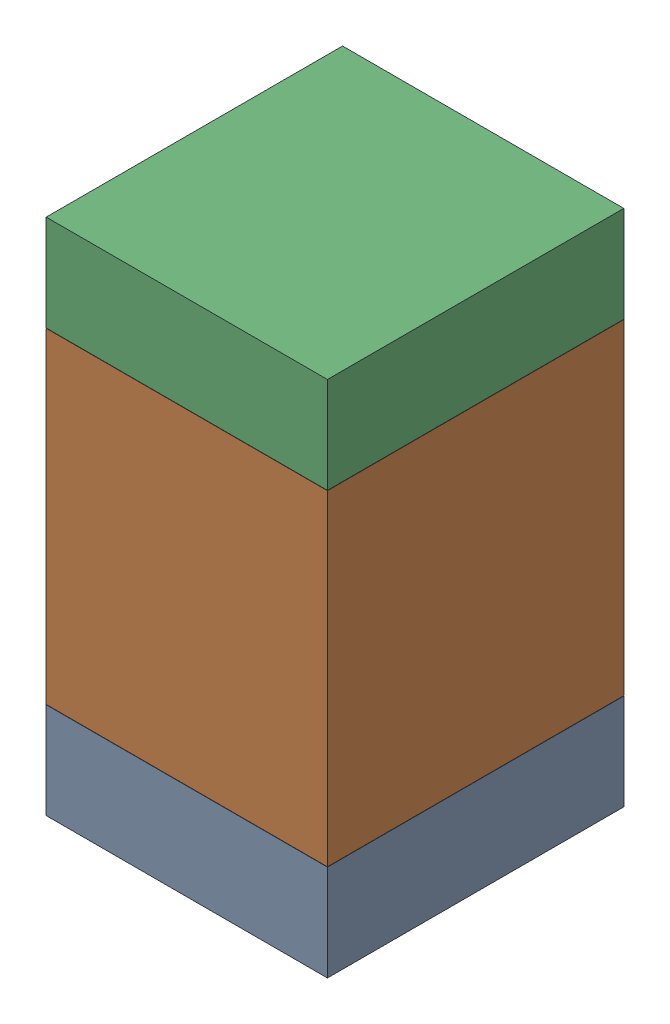
SolidWorks assembly R19, configuration Default. Lengths in mm.
Overall size (0.95 1.75 1).
6 component instances, 2 part files, 0 mates.
Components (placement in the parent):
- 6575495072-1: 6575495072 [Default] at (16.764 11.4795 0) size (0.95 0.32 1)
  - Extruded_6-1: Extruded_6 [Default] at origin size (0.95 0.32 1)
- 6575494912-1: 6575494912 [Default] at (16.764 12.192 0) size (0.95 1.1 1)
  - Extruded_7-1: Extruded_7 [Default] at origin size (0.95 1.1 1)
- 6575495072-2: 6575495072 [Default] at (16.764 12.9045 0) size (0.95 0.32 1)
  - Extruded_6-1: Extruded_6 [Default] at origin size (0.95 0.32 1)
